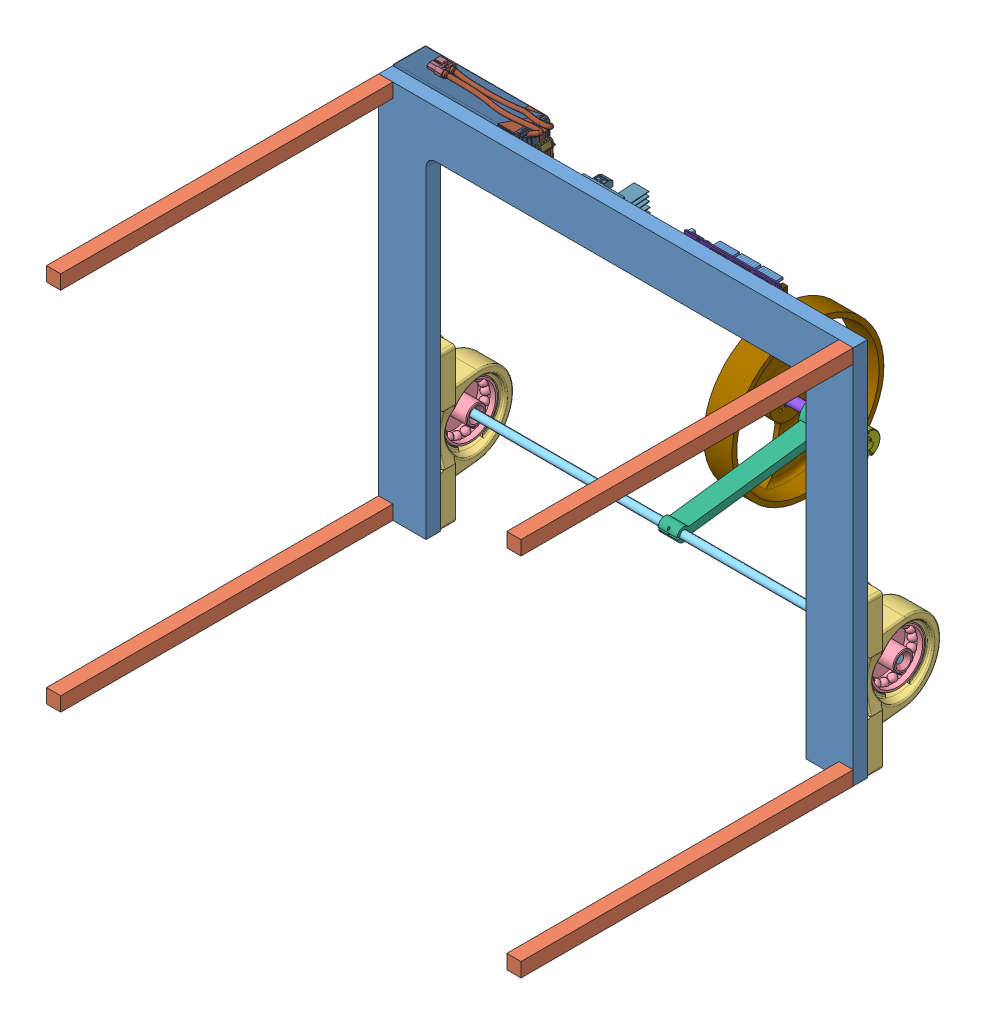
SolidWorks assembly assemmblage, configuration Défaut. Lengths in mm.
Overall size (510.81 410.44 661.31).
231 component instances, 45 part files, 35 mates.
Components (placement in the parent):
- chassit-1: chassit [Défaut] at (-83.3015 39.9713 342.5) size (500 400 15)
- pied châssis-1: pied châssis [Défaut] at (-325.8015 232.4713 357.5) size (15 15 350)
- pied châssis-2: pied châssis [Défaut] at (159.1985 232.4713 357.5) size (15 15 350)
- pied châssis-3: pied châssis [Défaut] at (-325.8015 -152.5287 357.5) size (15 15 350)
- pied châssis-4: pied châssis [Défaut] at (159.1985 -152.5287 357.5) size (15 15 350)
- PEDESTAL BEARING-1: PEDESTAL BEARING [Default] at (-180.6989 -135.1255 386.7537) x (0 1 0) z (-1 0 0) size (161.92 88.18 45.36)
  - BLOCK-1: BLOCK [Default] at (56.0593 88.7037 124.8276) size (161.93 85.72 45.36)
  - BEARING-1: BEARING [Default] at (56.0593 88.7037 124.8276) x (0.66028 0.75102 0) z (0 0 1) size (61.98 61.98 38.1)
- PEDESTAL BEARING-2: PEDESTAL BEARING [Default] at (269.3011 -135.1255 386.7537) x (0 1 0) z (-1 0 0) size (161.92 88.18 45.36)
  - BLOCK-1: BLOCK [Default] at (56.0593 88.7037 124.8276) size (161.93 85.72 45.36)
  - BEARING-1: BEARING [Default] at (56.0593 88.7037 124.8276) x (0.66028 0.75102 0) z (0 0 1) size (61.98 61.98 38.1)
- rail 8mm petit robot-1: rail 8mm petit robot [Défaut] at (-343.6515 -79.0662 298.05) x (0 0.560188 0.828366) z (1 0 0) size (8 8 500)
- bras petit moteur final-2: bras petit moteur final [Défaut] at (-91.3067 -70.0903 314.766) x (0 -0.12909 0.991633) z (1 0 0) size (183.09 32 22)
- JGA25-370 12V Planetary Geared Motor-1: JGA25-370 12V Planetary Geared Motor [Ratio 171 & 226] at (-91.3067 -58.7191 139.1808) x (0 -0.992165 -0.124934) z (0 0.124934 -0.992165) size (25.02 71.1 25)
- accouplement-2: accouplement [Défaut] at (-124.3067 -58.7191 139.1808) x (0 -0.900614 0.434621) z (1 0 0) size (12.88 12.77 31)
- reaction_wheel final-1: reaction_wheel final [Default] at (-129.3067 -58.7191 139.1808) x (0 0.983951 -0.178439) z (0 -0.178439 -0.983951) size (160 30 160)
- Bateria Lipo-1: Bateria Lipo [Predeterminado] at (-277.0558 356.4713 320.7738) x (-1 0 0) z (0 -1 0) size (148.26 35.01 60.86)
  - Funda de la bateria-1: Funda de la bateria [Predeterminado] at (-13.4133 -21.9262 140) size (140 35.01 50.88)
  - Nucleo de la bateria-1: Nucleo de la bateria [Predeterminado] at (-13.4133 -21.9262 140) size (145.58 35 59.73)
  - Conector-1: Conector [Predeterminado] at (-85.2332 -3.172 127.131) x (-0.20539 0.937139 -0.282108) z (-0.13236 0.259007 0.956764) size (14.8 5.7 7.75)
  - Conector XT60-1: Conector XT60 [Predeterminado] at (18.8662 -3.823 110.2533) x (0 -1 0) z (-1 0 0) size (15.6 8 21.81)
- L298N Stepper Motor Driver Assembly-1: L298N Stepper Motor Driver Assembly [Default] at (-80.6434 200.9696 349.7409) x (0 0.99727 0.073844) z (-1 0 0) size (43 28.01 43)
  - L298N Stepper Motor Driver (Red)-Part File-1: L298N Stepper Motor Driver (Red)-Part File [Default] at (16.8606 10.1012 32.1341) size (43 28.01 43)
  - pan head cross recess screw_iso_ISO 7045 - M1.6 x 4 - Z - 4N-1: pan head cross recess screw_iso_ISO 7045 - M1.6 x 4 - Z - 4N [Default] at (-1.3394 22.4012 35.9476) x (0 -1 0) z (-0.742963 0 0.669332) size (5.3 3.2 3.23)
  - pan head cross recess screw_iso_ISO 7045 - M1.6 x 4 - Z - 4N-2: pan head cross recess screw_iso_ISO 7045 - M1.6 x 4 - Z - 4N [Default] at (-1.3394 22.4012 41.5921) x (0 -1 0) z (-0.751552 0 0.659674) size (5.3 3.2 3.23)
  - pan head cross recess screw_iso_ISO 7045 - M1.6 x 4 - Z - 4N-3: pan head cross recess screw_iso_ISO 7045 - M1.6 x 4 - Z - 4N [Default] at (3.7852 22.4012 50.3107) x (0 -1 0) z (0.734198 0 -0.678936) size (5.3 3.2 3.23)
  - pan head cross recess screw_iso_ISO 7045 - M1.6 x 4 - Z - 4N-4: pan head cross recess screw_iso_ISO 7045 - M1.6 x 4 - Z - 4N [Default] at (14.2688 22.4012 50.3107) x (0 -1 0) z (0.720108 0 0.693862) size (5.3 3.2 3.23)
  - pan head cross recess screw_iso_ISO 7045 - M1.6 x 4 - Z - 4N-5: pan head cross recess screw_iso_ISO 7045 - M1.6 x 4 - Z - 4N [Default] at (9.027 22.4012 50.3107) x (0 -1 0) z (0.308372 0 0.951266) size (5.3 3.2 3.23)
  - pan head cross recess screw_iso_ISO 7045 - M1.6 x 4 - Z - 4N-6: pan head cross recess screw_iso_ISO 7045 - M1.6 x 4 - Z - 4N [Default] at (33.6606 22.4012 35.9476) x (0 -1 0) z (0 0 1) size (5.3 3.2 3.23)
  - pan head cross recess screw_iso_ISO 7045 - M1.6 x 4 - Z - 4N-7: pan head cross recess screw_iso_ISO 7045 - M1.6 x 4 - Z - 4N [Default] at (33.6606 22.4012 41.6421) x (0 -1 0) z (-0.222944 0 0.974831) size (5.3 3.2 3.23)
  - countersunk flat head cross recess screw_iso_ISO 7046-1 - M2.5 x 3 - Z - 3N-1: countersunk flat head cross recess screw_iso_ISO 7046-1 - M2.5 x 3 - Z - 3N [Default] at (16.3567 30.6012 21.6857) x (0 0 -1) z (-0.309066 0.951041 0) size (3 4.7 4.7)
- Arduino Mega ATmega 2560.STEP-1: Arduino Mega ATmega 2560.STEP [Défaut] at (24.1821 216.7713 342.5) x (-1 0 0) z (0 -1 0) size (109.91 15.26 53.6)
  - Arduino Mega PCB.STEP-1: Arduino Mega PCB.STEP [Défaut] at origin size (101.8 1.64 53.6)
  - headerFemalex18x2.STEP-1: headerFemalex18x2.STEP [Défaut] at (-44.415 1.63 17.88) x (0 0 -1) z (1 0 0) size (45.72 11.5 5.08)
  - headerFemale.STEP-1: headerFemale.STEP [Défaut] at (-30.205 1.63 24.23) size (2.54 11.5 2.54)
  - headerFemale.STEP-2: headerFemale.STEP [Défaut] at (-27.665 1.63 24.23) size (2.54 11.5 2.54)
  - headerFemale.STEP-3: headerFemale.STEP [Défaut] at (-25.125 1.63 24.23) size (2.54 11.5 2.54)
  - headerFemale.STEP-4: headerFemale.STEP [Défaut] at (-22.585 1.63 24.23) size (2.54 11.5 2.54)
  - headerFemale.STEP-5: headerFemale.STEP [Défaut] at (-20.045 1.63 24.23) size (2.54 11.5 2.54)
  - headerFemale.STEP-6: headerFemale.STEP [Défaut] at (-17.505 1.63 24.23) size (2.54 11.5 2.54)
  - headerFemale.STEP-7: headerFemale.STEP [Défaut] at (-14.965 1.63 24.23) size (2.54 11.5 2.54)
  - headerFemale.STEP-8: headerFemale.STEP [Défaut] at (-12.425 1.63 24.23) size (2.54 11.5 2.54)
  - headerFemale.STEP-9: headerFemale.STEP [Défaut] at (-7.345 1.63 24.23) size (2.54 11.5 2.54)
  - headerFemale.STEP-10: headerFemale.STEP [Défaut] at (-4.805 1.63 24.23) size (2.54 11.5 2.54)
  - headerFemale.STEP-11: headerFemale.STEP [Défaut] at (-2.265 1.63 24.23) size (2.54 11.5 2.54)
  - headerFemale.STEP-12: headerFemale.STEP [Défaut] at (0.275 1.63 24.23) size (2.54 11.5 2.54)
  - headerFemale.STEP-13: headerFemale.STEP [Défaut] at (2.815 1.63 24.23) size (2.54 11.5 2.54)
  - headerFemale.STEP-14: headerFemale.STEP [Défaut] at (5.355 1.63 24.23) size (2.54 11.5 2.54)
  - headerFemale.STEP-15: headerFemale.STEP [Défaut] at (7.895 1.63 24.23) size (2.54 11.5 2.54)
  - headerFemale.STEP-16: headerFemale.STEP [Défaut] at (10.435 1.63 24.23) size (2.54 11.5 2.54)
  - headerFemale.STEP-17: headerFemale.STEP [Défaut] at (15.515 1.63 24.23) size (2.54 11.5 2.54)
  - headerFemale.STEP-18: headerFemale.STEP [Défaut] at (18.055 1.63 24.23) size (2.54 11.5 2.54)
  - headerFemale.STEP-19: headerFemale.STEP [Défaut] at (20.595 1.63 24.23) size (2.54 11.5 2.54)
  - headerFemale.STEP-20: headerFemale.STEP [Défaut] at (23.135 1.63 24.23) size (2.54 11.5 2.54)
  - headerFemale.STEP-21: headerFemale.STEP [Défaut] at (25.675 1.63 24.23) size (2.54 11.5 2.54)
  - headerFemale.STEP-22: headerFemale.STEP [Défaut] at (28.215 1.63 24.23) size (2.54 11.5 2.54)
  - headerFemale.STEP-23: headerFemale.STEP [Défaut] at (30.755 1.63 24.23) size (2.54 11.5 2.54)
  - headerFemale.STEP-24: headerFemale.STEP [Défaut] at (33.295 1.63 24.23) size (2.54 11.5 2.54)
  - headerFemale.STEP-25: headerFemale.STEP [Défaut] at (35.835 1.63 24.23) size (2.54 11.5 2.54)
  - headerFemale.STEP-26: headerFemale.STEP [Défaut] at (38.375 1.63 24.23) size (2.54 11.5 2.54)
  - headerFemale.STEP-27: headerFemale.STEP [Défaut] at (-35.525 1.63 -24.23) size (2.54 11.5 2.54)
  - headerFemale.STEP-28: headerFemale.STEP [Défaut] at (-32.985 1.63 -24.23) size (2.54 11.5 2.54)
  - headerFemale.STEP-29: headerFemale.STEP [Défaut] at (-30.445 1.63 -24.23) size (2.54 11.5 2.54)
  - headerFemale.STEP-30: headerFemale.STEP [Défaut] at (-27.905 1.63 -24.23) size (2.54 11.5 2.54)
  - headerFemale.STEP-31: headerFemale.STEP [Défaut] at (-25.365 1.63 -24.23) size (2.54 11.5 2.54)
  - headerFemale.STEP-32: headerFemale.STEP [Défaut] at (-22.825 1.63 -24.23) size (2.54 11.5 2.54)
  - headerFemale.STEP-33: headerFemale.STEP [Défaut] at (-20.285 1.63 -24.23) size (2.54 11.5 2.54)
  - headerFemale.STEP-34: headerFemale.STEP [Défaut] at (-17.745 1.63 -24.23) size (2.54 11.5 2.54)
  - headerFemale.STEP-35: headerFemale.STEP [Défaut] at (-12.665 1.63 -24.23) size (2.54 11.5 2.54)
  - headerFemale.STEP-36: headerFemale.STEP [Défaut] at (-10.125 1.63 -24.23) size (2.54 11.5 2.54)
  - headerFemale.STEP-37: headerFemale.STEP [Défaut] at (-7.585 1.63 -24.23) size (2.54 11.5 2.54)
  - headerFemale.STEP-38: headerFemale.STEP [Défaut] at (-5.045 1.63 -24.23) size (2.54 11.5 2.54)
  - headerFemale.STEP-39: headerFemale.STEP [Défaut] at (-2.505 1.63 -24.23) size (2.54 11.5 2.54)
  - headerFemale.STEP-40: headerFemale.STEP [Défaut] at (0.035 1.63 -24.23) size (2.54 11.5 2.54)
  - headerFemale.STEP-41: headerFemale.STEP [Défaut] at (2.575 1.63 -24.23) size (2.54 11.5 2.54)
  - headerFemale.STEP-42: headerFemale.STEP [Défaut] at (5.115 1.63 -24.23) size (2.54 11.5 2.54)
  - headerFemale.STEP-43: headerFemale.STEP [Défaut] at (10.195 1.63 -24.23) size (2.54 11.5 2.54)
  - headerFemale.STEP-44: headerFemale.STEP [Défaut] at (12.735 1.63 -24.23) size (2.54 11.5 2.54)
  - headerFemale.STEP-45: headerFemale.STEP [Défaut] at (15.275 1.63 -24.23) size (2.54 11.5 2.54)
  - headerFemale.STEP-46: headerFemale.STEP [Défaut] at (17.815 1.63 -24.23) size (2.54 11.5 2.54)
  - headerFemale.STEP-47: headerFemale.STEP [Défaut] at (20.355 1.63 -24.23) size (2.54 11.5 2.54)
  - headerFemale.STEP-48: headerFemale.STEP [Défaut] at (22.895 1.63 -24.23) size (2.54 11.5 2.54)
  - headerFemale.STEP-49: headerFemale.STEP [Défaut] at (25.435 1.63 -24.23) size (2.54 11.5 2.54)
  - headerFemale.STEP-50: headerFemale.STEP [Défaut] at (27.975 1.63 -24.23) size (2.54 11.5 2.54)
  - solder.STEP-1: solder.STEP [Défaut] at (-46.9277 0 24.2186) x (-0.837169 0 -0.546944) z (-0.546944 0 0.837169) size (1.17 0.65 1.17)
  - solder.STEP-2: solder.STEP [Défaut] at (-44.3877 0 24.2186) x (-0.837169 0 -0.546944) z (-0.546944 0 0.837169) size (1.17 0.65 1.17)
  - solder.STEP-3: solder.STEP [Défaut] at (-46.9277 0 21.6786) x (-0.837169 0 -0.546944) z (-0.546944 0 0.837169) size (1.17 0.65 1.17)
  - solder.STEP-4: solder.STEP [Défaut] at (-44.3877 0 21.6786) x (-0.837169 0 -0.546944) z (-0.546944 0 0.837169) size (1.17 0.65 1.17)
  - solder.STEP-5: solder.STEP [Défaut] at (-46.9277 0 19.1386) x (-0.837169 0 -0.546944) z (-0.546944 0 0.837169) size (1.17 0.65 1.17)
  - solder.STEP-6: solder.STEP [Défaut] at (-44.3877 0 19.1386) x (-0.837169 0 -0.546944) z (-0.546944 0 0.837169) size (1.17 0.65 1.17)
  - solder.STEP-7: solder.STEP [Défaut] at (-46.9277 0 16.5986) x (-0.837169 0 -0.546944) z (-0.546944 0 0.837169) size (1.17 0.65 1.17)
  - solder.STEP-8: solder.STEP [Défaut] at (-44.3877 0 16.5986) x (-0.837169 0 -0.546944) z (-0.546944 0 0.837169) size (1.17 0.65 1.17)
  - solder.STEP-9: solder.STEP [Défaut] at (-46.9277 0 14.0586) x (-0.837169 0 -0.546944) z (-0.546944 0 0.837169) size (1.17 0.65 1.17)
  - solder.STEP-10: solder.STEP [Défaut] at (-44.3877 0 14.0586) x (-0.837169 0 -0.546944) z (-0.546944 0 0.837169) size (1.17 0.65 1.17)
  - solder.STEP-11: solder.STEP [Défaut] at (-46.9277 0 11.5186) x (-0.837169 0 -0.546944) z (-0.546944 0 0.837169) size (1.17 0.65 1.17)
  - solder.STEP-12: solder.STEP [Défaut] at (-44.3877 0 11.5186) x (-0.837169 0 -0.546944) z (-0.546944 0 0.837169) size (1.17 0.65 1.17)
  - solder.STEP-13: solder.STEP [Défaut] at (-46.9277 0 8.9786) x (-0.837169 0 -0.546944) z (-0.546944 0 0.837169) size (1.17 0.65 1.17)
  - solder.STEP-14: solder.STEP [Défaut] at (-44.3877 0 8.9786) x (-0.837169 0 -0.546944) z (-0.546944 0 0.837169) size (1.17 0.65 1.17)
  - solder.STEP-15: solder.STEP [Défaut] at (-46.9277 0 6.4386) x (-0.837169 0 -0.546944) z (-0.546944 0 0.837169) size (1.17 0.65 1.17)
  - solder.STEP-16: solder.STEP [Défaut] at (-44.3877 0 6.4386) x (-0.837169 0 -0.546944) z (-0.546944 0 0.837169) size (1.17 0.65 1.17)
  - solder.STEP-17: solder.STEP [Défaut] at (-46.9277 0 3.8986) x (-0.837169 0 -0.546944) z (-0.546944 0 0.837169) size (1.17 0.65 1.17)
  - solder.STEP-18: solder.STEP [Défaut] at (-44.3877 0 3.8986) x (-0.837169 0 -0.546944) z (-0.546944 0 0.837169) size (1.17 0.65 1.17)
  - solder.STEP-19: solder.STEP [Défaut] at (-46.9277 0 1.3586) x (-0.837169 0 -0.546944) z (-0.546944 0 0.837169) size (1.17 0.65 1.17)
  - solder.STEP-20: solder.STEP [Défaut] at (-44.3877 0 1.3586) x (-0.837169 0 -0.546944) z (-0.546944 0 0.837169) size (1.17 0.65 1.17)
  - solder.STEP-21: solder.STEP [Défaut] at (-46.9277 0 -1.1814) x (-0.837169 0 -0.546944) z (-0.546944 0 0.837169) size (1.17 0.65 1.17)
  - solder.STEP-22: solder.STEP [Défaut] at (-44.3877 0 -1.1814) x (-0.837169 0 -0.546944) z (-0.546944 0 0.837169) size (1.17 0.65 1.17)
  - solder.STEP-23: solder.STEP [Défaut] at (-46.9277 0 -3.7214) x (-0.837169 0 -0.546944) z (-0.546944 0 0.837169) size (1.17 0.65 1.17)
  - solder.STEP-24: solder.STEP [Défaut] at (-44.3877 0 -3.7214) x (-0.837169 0 -0.546944) z (-0.546944 0 0.837169) size (1.17 0.65 1.17)
  - solder.STEP-25: solder.STEP [Défaut] at (-46.9277 0 -6.2614) x (-0.837169 0 -0.546944) z (-0.546944 0 0.837169) size (1.17 0.65 1.17)
  - solder.STEP-26: solder.STEP [Défaut] at (-44.3877 0 -6.2614) x (-0.837169 0 -0.546944) z (-0.546944 0 0.837169) size (1.17 0.65 1.17)
  - solder.STEP-27: solder.STEP [Défaut] at (-46.9277 0 -8.8014) x (-0.837169 0 -0.546944) z (-0.546944 0 0.837169) size (1.17 0.65 1.17)
  - solder.STEP-28: solder.STEP [Défaut] at (-44.3877 0 -8.8014) x (-0.837169 0 -0.546944) z (-0.546944 0 0.837169) size (1.17 0.65 1.17)
  - solder.STEP-29: solder.STEP [Défaut] at (-46.9277 0 -11.3414) x (-0.837169 0 -0.546944) z (-0.546944 0 0.837169) size (1.17 0.65 1.17)
  - solder.STEP-30: solder.STEP [Défaut] at (-44.3877 0 -11.3414) x (-0.837169 0 -0.546944) z (-0.546944 0 0.837169) size (1.17 0.65 1.17)
  - solder.STEP-31: solder.STEP [Défaut] at (-46.9277 0 -13.8814) x (-0.837169 0 -0.546944) z (-0.546944 0 0.837169) size (1.17 0.65 1.17)
  - solder.STEP-32: solder.STEP [Défaut] at (-44.3877 0 -13.8814) x (-0.837169 0 -0.546944) z (-0.546944 0 0.837169) size (1.17 0.65 1.17)
  - solder.STEP-33: solder.STEP [Défaut] at (-46.9277 0 -16.4214) x (-0.837169 0 -0.546944) z (-0.546944 0 0.837169) size (1.17 0.65 1.17)
  - solder.STEP-34: solder.STEP [Défaut] at (-44.3877 0 -16.4214) x (-0.837169 0 -0.546944) z (-0.546944 0 0.837169) size (1.17 0.65 1.17)
  - solder.STEP-35: solder.STEP [Défaut] at (-46.9277 0 -18.9614) x (-0.837169 0 -0.546944) z (-0.546944 0 0.837169) size (1.17 0.65 1.17)
  - solder.STEP-36: solder.STEP [Défaut] at (-44.3877 0 -18.9614) x (-0.837169 0 -0.546944) z (-0.546944 0 0.837169) size (1.17 0.65 1.17)
  - solder.STEP-37: solder.STEP [Défaut] at (-36.5404 0 24.2186) x (-0.837169 0 -0.546944) z (-0.546944 0 0.837169) size (1.17 0.65 1.17)
  - solder.STEP-38: solder.STEP [Défaut] at (-34.0004 0 24.2186) x (-0.837169 0 -0.546944) z (-0.546944 0 0.837169) size (1.17 0.65 1.17)
  - solder.STEP-39: solder.STEP [Défaut] at (-31.4604 0 24.2186) x (-0.837169 0 -0.546944) z (-0.546944 0 0.837169) size (1.17 0.65 1.17)
  - solder.STEP-40: solder.STEP [Défaut] at (-28.9204 0 24.2186) x (-0.837169 0 -0.546944) z (-0.546944 0 0.837169) size (1.17 0.65 1.17)
  - solder.STEP-41: solder.STEP [Défaut] at (-26.3804 0 24.2186) x (-0.837169 0 -0.546944) z (-0.546944 0 0.837169) size (1.17 0.65 1.17)
  - solder.STEP-42: solder.STEP [Défaut] at (-23.8404 0 24.2186) x (-0.837169 0 -0.546944) z (-0.546944 0 0.837169) size (1.17 0.65 1.17)
  - solder.STEP-43: solder.STEP [Défaut] at (-21.3004 0 24.2186) x (-0.837169 0 -0.546944) z (-0.546944 0 0.837169) size (1.17 0.65 1.17)
  - solder.STEP-44: solder.STEP [Défaut] at (-18.7604 0 24.2186) x (-0.837169 0 -0.546944) z (-0.546944 0 0.837169) size (1.17 0.65 1.17)
  - solder.STEP-45: solder.STEP [Défaut] at (-13.6804 0 24.2186) x (-0.837169 0 -0.546944) z (-0.546944 0 0.837169) size (1.17 0.65 1.17)
  - solder.STEP-46: solder.STEP [Défaut] at (-11.1404 0 24.2186) x (-0.837169 0 -0.546944) z (-0.546944 0 0.837169) size (1.17 0.65 1.17)
  - solder.STEP-47: solder.STEP [Défaut] at (-8.6004 0 24.2186) x (-0.837169 0 -0.546944) z (-0.546944 0 0.837169) size (1.17 0.65 1.17)
  - solder.STEP-48: solder.STEP [Défaut] at (-6.0604 0 24.2186) x (-0.837169 0 -0.546944) z (-0.546944 0 0.837169) size (1.17 0.65 1.17)
  - solder.STEP-49: solder.STEP [Défaut] at (-3.5204 0 24.2186) x (-0.837169 0 -0.546944) z (-0.546944 0 0.837169) size (1.17 0.65 1.17)
  - solder.STEP-50: solder.STEP [Défaut] at (-0.9804 0 24.2186) x (-0.837169 0 -0.546944) z (-0.546944 0 0.837169) size (1.17 0.65 1.17)
  - solder.STEP-51: solder.STEP [Défaut] at (1.5596 0 24.2186) x (-0.837169 0 -0.546944) z (-0.546944 0 0.837169) size (1.17 0.65 1.17)
  - solder.STEP-52: solder.STEP [Défaut] at (4.0996 0 24.2186) x (-0.837169 0 -0.546944) z (-0.546944 0 0.837169) size (1.17 0.65 1.17)
  - solder.STEP-53: solder.STEP [Défaut] at (9.1796 0 24.2186) x (-0.837169 0 -0.546944) z (-0.546944 0 0.837169) size (1.17 0.65 1.17)
  - solder.STEP-54: solder.STEP [Défaut] at (11.7196 0 24.2186) x (-0.837169 0 -0.546944) z (-0.546944 0 0.837169) size (1.17 0.65 1.17)
  - solder.STEP-55: solder.STEP [Défaut] at (14.2596 0 24.2186) x (-0.837169 0 -0.546944) z (-0.546944 0 0.837169) size (1.17 0.65 1.17)
  - solder.STEP-56: solder.STEP [Défaut] at (16.7996 0 24.2186) x (-0.837169 0 -0.546944) z (-0.546944 0 0.837169) size (1.17 0.65 1.17)
  - solder.STEP-57: solder.STEP [Défaut] at (19.3396 0 24.2186) x (-0.837169 0 -0.546944) z (-0.546944 0 0.837169) size (1.17 0.65 1.17)
  - solder.STEP-58: solder.STEP [Défaut] at (21.8796 0 24.2186) x (-0.837169 0 -0.546944) z (-0.546944 0 0.837169) size (1.17 0.65 1.17)
  - solder.STEP-59: solder.STEP [Défaut] at (24.4196 0 24.2186) x (-0.837169 0 -0.546944) z (-0.546944 0 0.837169) size (1.17 0.65 1.17)
  - solder.STEP-60: solder.STEP [Défaut] at (26.9596 0 24.2186) x (-0.837169 0 -0.546944) z (-0.546944 0 0.837169) size (1.17 0.65 1.17)
  - solder.STEP-61: solder.STEP [Défaut] at (29.4996 0 24.2186) x (-0.837169 0 -0.546944) z (-0.546944 0 0.837169) size (1.17 0.65 1.17)
  - solder.STEP-62: solder.STEP [Défaut] at (32.0396 0 24.2186) x (-0.837169 0 -0.546944) z (-0.546944 0 0.837169) size (1.17 0.65 1.17)
  - solder.STEP-63: solder.STEP [Défaut] at (-41.8709 0 -24.251) x (-0.837169 0 -0.546944) z (-0.546944 0 0.837169) size (1.17 0.65 1.17)
  - solder.STEP-64: solder.STEP [Défaut] at (-39.3309 0 -24.251) x (-0.837169 0 -0.546944) z (-0.546944 0 0.837169) size (1.17 0.65 1.17)
  - solder.STEP-65: solder.STEP [Défaut] at (-36.7909 0 -24.251) x (-0.837169 0 -0.546944) z (-0.546944 0 0.837169) size (1.17 0.65 1.17)
  - solder.STEP-66: solder.STEP [Défaut] at (-34.2509 0 -24.251) x (-0.837169 0 -0.546944) z (-0.546944 0 0.837169) size (1.17 0.65 1.17)
  - solder.STEP-67: solder.STEP [Défaut] at (-31.7109 0 -24.251) x (-0.837169 0 -0.546944) z (-0.546944 0 0.837169) size (1.17 0.65 1.17)
  - solder.STEP-68: solder.STEP [Défaut] at (-29.1709 0 -24.251) x (-0.837169 0 -0.546944) z (-0.546944 0 0.837169) size (1.17 0.65 1.17)
  - solder.STEP-69: solder.STEP [Défaut] at (-26.6309 0 -24.251) x (-0.837169 0 -0.546944) z (-0.546944 0 0.837169) size (1.17 0.65 1.17)
  - solder.STEP-70: solder.STEP [Défaut] at (-24.0909 0 -24.251) x (-0.837169 0 -0.546944) z (-0.546944 0 0.837169) size (1.17 0.65 1.17)
  - solder.STEP-71: solder.STEP [Défaut] at (-19.0109 0 -24.251) x (-0.837169 0 -0.546944) z (-0.546944 0 0.837169) size (1.17 0.65 1.17)
  - solder.STEP-72: solder.STEP [Défaut] at (-16.4709 0 -24.251) x (-0.837169 0 -0.546944) z (-0.546944 0 0.837169) size (1.17 0.65 1.17)
  - solder.STEP-73: solder.STEP [Défaut] at (-13.9309 0 -24.251) x (-0.837169 0 -0.546944) z (-0.546944 0 0.837169) size (1.17 0.65 1.17)
  - solder.STEP-74: solder.STEP [Défaut] at (-11.3909 0 -24.251) x (-0.837169 0 -0.546944) z (-0.546944 0 0.837169) size (1.17 0.65 1.17)
  - solder.STEP-75: solder.STEP [Défaut] at (-8.8509 0 -24.251) x (-0.837169 0 -0.546944) z (-0.546944 0 0.837169) size (1.17 0.65 1.17)
  - solder.STEP-76: solder.STEP [Défaut] at (-6.3109 0 -24.251) x (-0.837169 0 -0.546944) z (-0.546944 0 0.837169) size (1.17 0.65 1.17)
  - solder.STEP-77: solder.STEP [Défaut] at (-3.7709 0 -24.251) x (-0.837169 0 -0.546944) z (-0.546944 0 0.837169) size (1.17 0.65 1.17)
  - solder.STEP-78: solder.STEP [Défaut] at (-1.2309 0 -24.251) x (-0.837169 0 -0.546944) z (-0.546944 0 0.837169) size (1.17 0.65 1.17)
  - solder.STEP-79: solder.STEP [Défaut] at (3.8491 0 -24.251) x (-0.837169 0 -0.546944) z (-0.546944 0 0.837169) size (1.17 0.65 1.17)
  - solder.STEP-80: solder.STEP [Défaut] at (6.3891 0 -24.251) x (-0.837169 0 -0.546944) z (-0.546944 0 0.837169) size (1.17 0.65 1.17)
  - solder.STEP-81: solder.STEP [Défaut] at (8.9291 0 -24.251) x (-0.837169 0 -0.546944) z (-0.546944 0 0.837169) size (1.17 0.65 1.17)
  - solder.STEP-82: solder.STEP [Défaut] at (11.4691 0 -24.251) x (-0.837169 0 -0.546944) z (-0.546944 0 0.837169) size (1.17 0.65 1.17)
  - solder.STEP-83: solder.STEP [Défaut] at (14.0091 0 -24.251) x (-0.837169 0 -0.546944) z (-0.546944 0 0.837169) size (1.17 0.65 1.17)
  - solder.STEP-84: solder.STEP [Défaut] at (16.5491 0 -24.251) x (-0.837169 0 -0.546944) z (-0.546944 0 0.837169) size (1.17 0.65 1.17)
  - solder.STEP-85: solder.STEP [Défaut] at (19.0891 0 -24.251) x (-0.837169 0 -0.546944) z (-0.546944 0 0.837169) size (1.17 0.65 1.17)
  - solder.STEP-86: solder.STEP [Défaut] at (21.6291 0 -24.251) x (-0.837169 0 -0.546944) z (-0.546944 0 0.837169) size (1.17 0.65 1.17)
  - USBInput.STEP-1: USBInput.STEP [Défaut] at (51.825 1.63 -24.14) x (0 0 1) z (-1 0 0) size (13.91 15.21 16.51)
  - solder.STEP-87: solder.STEP [Défaut] at (43.2353 0 12.6794) x (-0.837169 0 -0.546944) z (-0.546944 0 0.837169) size (1.17 0.65 1.17)
  - solder1.8.STEP-1: solder1.8.STEP [Défaut] at (47.8972 0 19.9763) x (-0.837169 0 -0.546944) z (-0.546944 0 0.837169) size (1.8 0.65 1.8)
  - solder1.8.STEP-2: solder1.8.STEP [Défaut] at (47.8972 0 7.7416) x (-0.837169 0 -0.546944) z (-0.546944 0 0.837169) size (1.8 0.65 1.8)
  - solder.STEP-88: solder.STEP [Défaut] at (43.2353 0 15.1294) x (-0.837169 0 -0.546944) z (-0.546944 0 0.837169) size (1.17 0.65 1.17)
  - solder.STEP-89: solder.STEP [Défaut] at (45.1853 0 12.6794) x (-0.837169 0 -0.546944) z (-0.546944 0 0.837169) size (1.17 0.65 1.17)
  - solder.STEP-90: solder.STEP [Défaut] at (45.1853 0 15.1294) x (-0.837169 0 -0.546944) z (-0.546944 0 0.837169) size (1.17 0.65 1.17)
  - PowerPlug.STEP-1: PowerPlug.STEP [Défaut] at (53.07 1.63 -23.075) x (0 0 1) z (-1 0 0) size (11.2 15.2 15.9)
  - smdPushButton.STEP-1: smdPushButton.STEP [Défaut] at (-25.845 1.63 0) x (0 0 -1) z (1 0 0) size (9.1 2.85 5.6)
  - headerMale.STEP-1: headerMale.STEP [Défaut] at (-17.525 1.63 2.54) size (2.54 11.1 2.54)
  - headerMale.STEP-2: headerMale.STEP [Défaut] at (-17.525 1.63 0.09) size (2.54 11.1 2.54)
  - headerMale.STEP-3: headerMale.STEP [Défaut] at (-17.525 1.63 -2.36) size (2.54 11.1 2.54)
  - headerMale.STEP-4: headerMale.STEP [Défaut] at (-14.985 1.63 2.54) size (2.54 11.1 2.54)
  - headerMale.STEP-5: headerMale.STEP [Défaut] at (-14.985 1.63 0.09) size (2.54 11.1 2.54)
  - headerMale.STEP-6: headerMale.STEP [Défaut] at (-14.985 1.63 -2.36) size (2.54 11.1 2.54)
  - smd47.STEP-1: smd47.STEP [Défaut] at (33.2359 2.48 -17.65) x (0 0 1) z (-1 0 0) size (9.5 5.61 6.5)
  - smd47.STEP-2: smd47.STEP [Défaut] at (26.7359 2.48 -17.65) x (0 0 1) z (-1 0 0) size (9.5 5.61 6.5)
  - smdM7diode.STEP-1: smdM7diode.STEP [Défaut] at (28.3956 1.68 -24.2569) size (6.5 2.06 2.5)
  - smdCrystalOscillator.STEP-1: smdCrystalOscillator.STEP [Défaut] at (29.1027 1.83 15.1887) size (11.93 3.7 4.5)
  - VoltageRegulatorAMS1112.STEP-1: VoltageRegulatorAMS1112.STEP [Défaut] at (46.1008 1.63 -6.698) x (-0.008727 0 0.999962) z (-0.999962 0 -0.008727) size (5.5 1.65 6.7)
  - smdChip16pin.STEP-1: smdChip16pin.STEP [Défaut] at (36.9716 2.355 6.6448) x (0 0 1) z (-1 0 0) size (7.3 1.22 10)
  - tinyVoltageRegulator.STEP-1: tinyVoltageRegulator.STEP [Défaut] at (44.8587 1.63 1.7682) x (-0.008727 0 0.999962) z (-0.999962 0 -0.008727) size (2.75 0.7 2.1)
  - smdResistor102.STEP-1: smdResistor102.STEP [Défaut] at (15.0665 1.63 -5.1619) size (2.53 0.63 1.31)
  - smdResistor102.STEP-2: smdResistor102.STEP [Défaut] at (18.9101 1.63 -5.1619) size (2.53 0.63 1.31)
  - smdLED.STEP-1: smdLED.STEP [Défaut] at (15.1024 1.68 -8.0155) size (3.23 0.89 1.26)
  - smdLED.STEP-2: smdLED.STEP [Défaut] at (18.924 1.68 -8.0155) size (3.23 0.89 1.26)
  - tinyCrystal.STEP-1: tinyCrystal.STEP [Défaut] at (17.0851 1.63 -14.2329) x (-0.008727 0 0.999962) z (-0.999962 0 -0.008727) size (3.1 0.8 1.45)
  - smdceramiccapacitorwhite.STEP-1: smdceramiccapacitorwhite.STEP [Défaut] at (15.9897 1.63 -17.0687) size (2.52 0.61 1.3)
  - smdceramiccapacitorwhite.STEP-2: smdceramiccapacitorwhite.STEP [Défaut] at (15.9897 1.63 -11.5964) size (2.52 0.61 1.3)
  - smdResistor105.STEP-1: smdResistor105.STEP [Défaut] at (14.9012 1.63 -14.3439) x (0.008727 0 -0.999962) z (0.999962 0 0.008727) size (2.53 0.63 1.31)
  - tinyDiode.STEP-1: tinyDiode.STEP [Défaut] at (19.1387 1.64 -14.1257) x (0.008727 0 -0.999962) z (0.999962 0 0.008727) size (2.77 0.81 1)
  - smdResistor103.STEP-1: smdResistor103.STEP [Défaut] at (30.4879 1.63 -4.0203) size (2.53 0.63 1.31)
  - smdResistor103.STEP-2: smdResistor103.STEP [Défaut] at (34.5333 1.63 -4.0924) size (2.53 0.63 1.31)
  - smdceramiccapacitor.STEP-1: smdceramiccapacitor.STEP [Défaut] at (38.0044 1.63 -4.0975) size (2.52 0.61 1.3)
  - smdceramiccapacitor.STEP-2: smdceramiccapacitor.STEP [Défaut] at (34.4647 1.63 -7.4993) x (0.008727 0 -0.999962) z (0.999962 0 0.008727) size (2.52 0.61 1.3)
  - smdceramiccapacitor.STEP-3: smdceramiccapacitor.STEP [Défaut] at (26.4038 1.7166 -4.0641) size (2.52 0.61 1.3)
  - tinyVoltageRegulator5pins.STEP-1: tinyVoltageRegulator5pins.STEP [Défaut] at (36.9485 1.63 -7.6363) x (-0.008727 0 0.999962) z (-0.999962 0 -0.008727) size (2.75 0.7 2.1)
  - smdceramiccapacitorwhite.STEP-3: smdceramiccapacitorwhite.STEP [Défaut] at (22.5361 1.63 10.8878) size (2.52 0.61 1.3)
  - smdceramiccapacitor.STEP-4: smdceramiccapacitor.STEP [Défaut] at (22.5508 1.63 8.9496) size (2.52 0.61 1.3)
  - smdResistor102.STEP-3: smdResistor102.STEP [Défaut] at (22.6192 1.63 6.9092) size (2.53 0.63 1.31)
  - smdResistor102.STEP-4: smdResistor102.STEP [Défaut] at (22.6192 1.63 5.022) size (2.53 0.63 1.31)
  - smdResistorNoNumber.STEP-1: smdResistorNoNumber.STEP [Défaut] at (22.6869 1.63 3.0647) size (2.53 0.62 1.31)
  - smdResistorNoNumber.STEP-2: smdResistorNoNumber.STEP [Défaut] at (22.6869 1.63 1.2353) size (2.53 0.62 1.31)
  - smdceramiccapacitor.STEP-5: smdceramiccapacitor.STEP [Défaut] at (22.5508 1.63 -0.8918) size (2.52 0.61 1.3)
  - smdceramiccapacitor.STEP-6: smdceramiccapacitor.STEP [Défaut] at (18.6684 1.63 10.7899) size (2.52 0.61 1.3)
  - smdResistor103.STEP-3: smdResistor103.STEP [Défaut] at (18.6293 1.63 8.8506) size (2.53 0.63 1.31)
  - smdLED.STEP-3: smdLED.STEP [Défaut] at (18.6733 1.68 6.7615) size (3.23 0.89 1.26)
  - smdLED.STEP-4: smdLED.STEP [Défaut] at (18.6733 1.68 4.9107) size (3.23 0.89 1.26)
  - smdceramiccapacitor.STEP-7: smdceramiccapacitor.STEP [Défaut] at (39.1596 1.63 19.5386) size (2.52 0.61 1.3)
  - smdceramiccapacitor.STEP-8: smdceramiccapacitor.STEP [Défaut] at (39.1596 1.63 17.5628) size (2.52 0.61 1.3)
  - smdceramiccapacitor.STEP-9: smdceramiccapacitor.STEP [Défaut] at (39.1596 1.63 7.9308) size (2.52 0.61 1.3)
  - smdResistorNoNumber.STEP-3: smdResistorNoNumber.STEP [Défaut] at (39.1794 1.63 11.6814) size (2.53 0.62 1.31)
  - smdResistorNoNumber.STEP-4: smdResistorNoNumber.STEP [Défaut] at (39.1794 1.63 13.8493) size (2.53 0.62 1.31)
  - 1.7mmSmdCeramicCapacitorgray.STEP-1: 1.7mmSmdCeramicCapacitorgray.STEP [Défaut] at (39.277 1.5726 15.6439) size (2.02 0.49 1.04)
  - 1.7mmSmdCeramicCapacitorgray.STEP-2: 1.7mmSmdCeramicCapacitorgray.STEP [Défaut] at (39.277 1.5726 9.803) size (2.02 0.49 1.04)
  - CrystalNo5.STEP-1: CrystalNo5.STEP [Défaut] at (48.5405 1.68 1.8508) x (0.008727 0 -0.999962) z (0.999962 0 0.008727) size (2.54 0.66 1.44)
  - smdceramiccapacitorwhite.STEP-4: smdceramiccapacitorwhite.STEP [Défaut] at (33.3846 1.63 18.6432) size (2.52 0.61 1.3)
  - smdceramiccapacitorwhite.STEP-5: smdceramiccapacitorwhite.STEP [Défaut] at (25.6965 1.63 18.6432) size (2.52 0.61 1.3)
  - smdResistor105.STEP-2: smdResistor105.STEP [Défaut] at (29.3693 1.63 18.6473) size (2.53 0.63 1.31)
  - smdChip8pin.STEP-1: smdChip8pin.STEP [Défaut] at (28.6276 2.355 -10.7802) size (7.3 1.22 4.5)
  - ATmega 2560.STEP-1: ATmega 2560.STEP [Défaut] at (0.3651 1.63 0.2251) size (16.31 1.01 16.31)
Mates (geometry in assembly coordinates):
- Coincident1: coincident: plane of chassit-1 through (-273.3015 179.9713 357.5) normal (0 0 1); plane of pied châssis-1 through (-325.8015 232.4713 357.5) normal (0 0 -1)
- Coincident2: coincident: line of chassit-1 through (166.6985 239.9713 357.5) axis (-1 0 0); line of pied châssis-1 through (-318.3015 239.9713 357.5) axis (-1 0 0)
- Coincident3: coincident: line of chassit-1 through (-333.3015 239.9713 357.5) axis (0 -1 0); line of pied châssis-1 through (-333.3015 239.9713 357.5) axis (0 -1 0)
- Coincident4: coincident: plane of chassit-1 through (-273.3015 179.9713 357.5) normal (0 0 1); plane of pied châssis-2 through (159.1985 232.4713 357.5) normal (0 0 -1)
- Coincident5: coincident: line of chassit-1 through (166.6985 239.9713 357.5) axis (-1 0 0); line of pied châssis-2 through (166.6985 239.9713 357.5) axis (-1 0 0)
- Coincident6: coincident: line of chassit-1 through (166.6985 -160.0287 357.5) axis (0 1 0); line of pied châssis-2 through (166.6985 224.9713 357.5) axis (0 1 0)
- Coincident7: coincident: plane of chassit-1 through (-273.3015 179.9713 357.5) normal (0 0 1); plane of pied châssis-3 through (-325.8015 -152.5287 357.5) normal (0 0 -1)
- Coincident8: coincident: line of chassit-1 through (-333.3015 239.9713 357.5) axis (0 -1 0); line of pied châssis-3 through (-333.3015 -145.0287 357.5) axis (0 -1 0)
- Coincident9: coincident: line of chassit-1 through (-333.3015 -160.0287 357.5) axis (1 0 0); plane of pied châssis-3 through (-333.3015 -160.0287 707.5) normal (0 -1 0)
- Coincident10: coincident: plane of chassit-1 through (-273.3015 179.9713 357.5) normal (0 0 1); plane of pied châssis-4 through (159.1985 -152.5287 357.5) normal (0 0 -1)
- Coincident11: coincident: line of chassit-1 through (166.6985 -160.0287 357.5) axis (0 1 0); line of pied châssis-4 through (166.6985 -160.0287 357.5) axis (0 1 0)
- Coincident12: coincident: line of chassit-1 through (116.6985 -160.0287 357.5) axis (1 0 0); line of pied châssis-4 through (151.6985 -160.0287 357.5) axis (1 0 0)
- Coincident19: coincident: line of chassit-1 through (-333.3015 -160.0287 342.5) axis (1 0 0); line of PEDESTAL BEARING-1/BLOCK-1 through (-324.5765 -160.0287 342.5) axis (1 0 0)
- Coincident20: coincident: line of chassit-1 through (-283.3015 -160.0287 342.5) axis (0 1 0); line of PEDESTAL BEARING-1/BLOCK-1 through (-283.3015 -156.8537 342.5) axis (0 1 0)
- Coincident21: coincident: line of chassit-1 through (116.6985 -160.0287 342.5) axis (1 0 0); line of PEDESTAL BEARING-2/BLOCK-1 through (125.4235 -160.0287 342.5) axis (1 0 0)
- Coincident22: coincident: line of chassit-1 through (166.6985 -160.0287 342.5) axis (0 1 0); line of PEDESTAL BEARING-2/BLOCK-1 through (166.6985 -156.8537 342.5) axis (0 1 0)
- Concentric4: concentric: cylinder of rail 8mm petit robot-1 through (156.3485 -79.0662 298.05) axis (-1 0 0) radius 4; cylinder of bras petit moteur final-2 through (-71.3067 -79.0662 298.05) axis (-1 0 0) radius 4.15
- Coincident24: coincident: circle of PEDESTAL BEARING-2/BEARING-1; circle of rail 8mm petit robot-1
- Lock2: lock: unknown of rail 8mm petit robot-1; unknown of bras petit moteur final-2
- Coincident25: coincident: plane of bras petit moteur final-2 through (-91.3067 -15.3023 151.1229) normal (1 0 0); plane of JGA25-370 12V Planetary Geared Motor-1 through (-91.3067 -15.3023 151.1229) normal (-1 0 0)
- Concentric6: concentric: cylinder of bras petit moteur final-2 through (-71.3067 -15.3023 151.1229) axis (-1 0 0) radius 12.75; cylinder of JGA25-370 12V Planetary Geared Motor-1 through (908.6933 -15.3023 151.1229) axis (1 0 0) radius 12.5
- Lock3: lock: unknown of bras petit moteur final-2; unknown of JGA25-370 12V Planetary Geared Motor-1
- Concentric8: concentric: cylinder of accouplement-2 through (-93.3067 -15.3023 151.1229) axis (-1 0 0) radius 3; circle of reaction_wheel final-1
- Coincident36: coincident: circle of accouplement-2; circle of reaction_wheel final-1
- Concentric10: concentric: circle of JGA25-370 12V Planetary Geared Motor-1; circle of accouplement-2
- Lock9: lock: unknown of accouplement-2; unknown of reaction_wheel final-1
- Coincident38: coincident: plane of bras petit moteur final-2 through (-93.3067 -15.3023 151.1229) normal (-1 0 0); plane of accouplement-2 through (-93.3067 -15.3023 151.1229) normal (1 0 0)
- Coincident39: coincident: plane of chassit-1 through (-273.3015 179.9713 342.5) normal (0 0 -1); plane of Bateria Lipo-1/Nucleo de la bateria-1 through (-263.6425 216.4713 342.7) normal (0 0 1)
- Parallel2: parallel: line of chassit-1 through (-333.3015 239.9713 342.5) axis (0 -1 0); line of Bateria Lipo-1/Nucleo de la bateria-1 through (-333.6425 192.9713 341.2) axis (0 1 0)
- Coincident43: coincident: line of chassit-1 through (166.6985 239.9713 342.5) axis (-1 0 0); line of Bateria Lipo-1/Nucleo de la bateria-1 through (-210.4235 239.9713 342.5) axis (-1 0 0)
- Lock10: lock: unknown of chassit-1; unknown of ?
- Coincident49: coincident: line of chassit-1 through (166.6985 239.9713 342.5) axis (-1 0 0); line of L298N Stepper Motor Driver Assembly-1/L298N Stepper Motor Driver (Red)-Part File-1 through (-134.2775 239.9713 342.5) axis (1 0 0)
- Coincident50: coincident: plane of chassit-1 through (-273.3015 179.9713 342.5) normal (0 0 -1); plane of Arduino Mega ATmega 2560.STEP-1/Arduino Mega PCB.STEP-1 through (24.1821 216.7713 342.5) normal (0 0 1)
- Coincident52: coincident: line of chassit-1 through (-273.3015 189.9713 342.5) axis (1 0 0); plane of Arduino Mega ATmega 2560.STEP-1/Arduino Mega PCB.STEP-1 through (71.4071 189.9713 340.87) normal (0 -1 0)
- Lock11: lock: unknown of chassit-1; unknown of Arduino Mega ATmega 2560.STEP-1/Arduino Mega PCB.STEP-1
